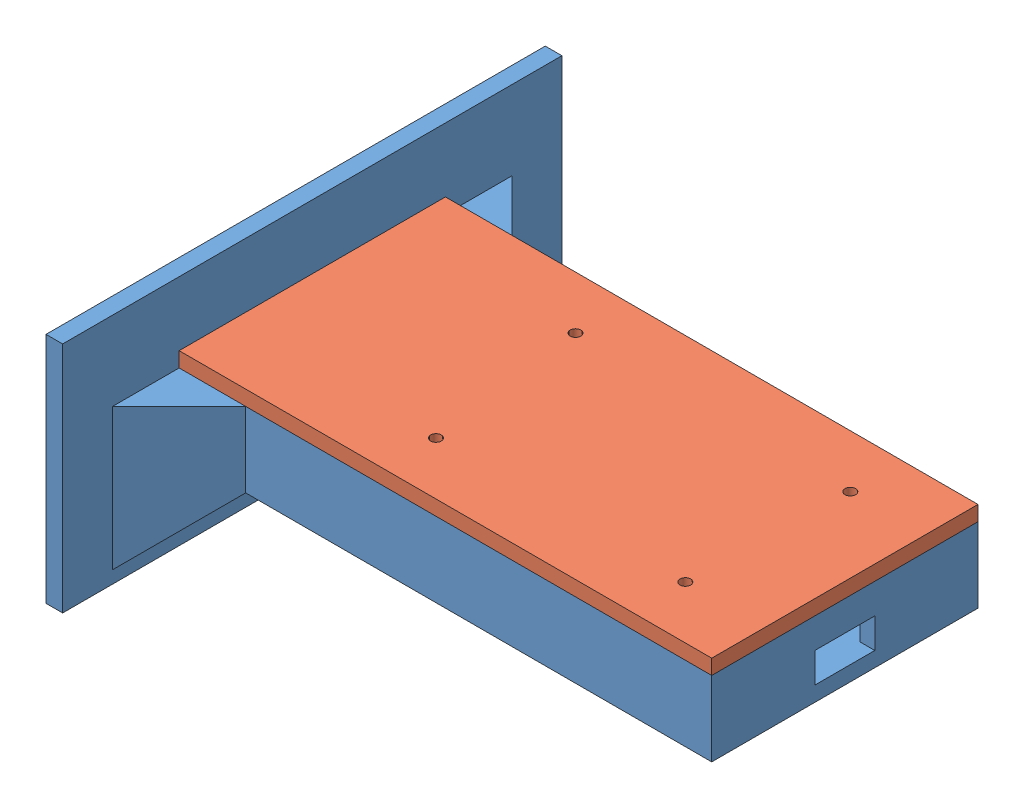
SolidWorks assembly RGB_beaconASSEMBLY, configuration Default. Lengths in mm.
Overall size (165 70 150).
2 component instances, 2 part files, 5 mates.
Components (placement in the parent):
- RGV_beacon_mount-1: RGV_beacon_mount [Default] at origin size (165 70 150)
- RGV_mount_TOP-PLATE-1: RGV_mount_TOP-PLATE [Default] at (0 27 0) x (0 -1 0) z (0 0 1) size (4.5 160 80)
Mates (geometry in assembly coordinates):
- Coincident1: coordinate: point of RGV_beacon_mount-1
- Coincident4: coincident aligned: circle of RGV_beacon_mount-1; circle of nrf52833dk.step-1/Board.step-1/Open CASCADE STEP translator 7.5 1.1.1.step-1
- Concentric1: concentric: cylinder of RGV_beacon_mount-1 through (57.5 -8.5 -24.14) axis (0 1 0) radius 1.6; cylinder of RGV_mount_TOP-PLATE-1 through (57.5 22.5 -24.14) axis (0 1 0) radius 1.6
- Concentric2: concentric: cylinder of RGV_beacon_mount-1 through (-18.7 -8.5 24.14) axis (0 1 0) radius 1.6; cylinder of RGV_mount_TOP-PLATE-1 through (-18.7 22.5 24.14) axis (0 1 0) radius 1.6
- Coincident5: coincident anti-aligned: plane of RGV_beacon_mount-1 through (0 22.5 0) normal (0 1 0); plane of RGV_mount_TOP-PLATE-1 through (0 22.5 0) normal (0 -1 0)
